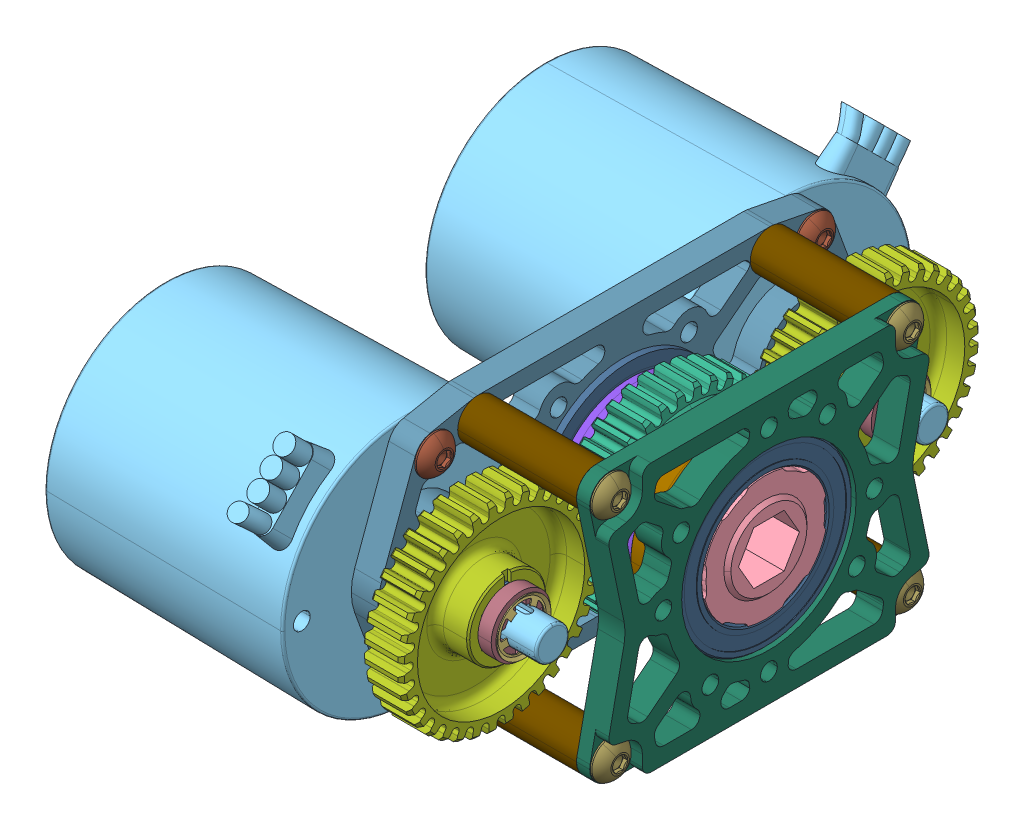
SolidWorks assembly REV Elevator Motor, configuration Default. Lengths in mm.
Overall size (99.54 69.01 161.62).
39 component instances, 18 part files, 0 mates.
Components (placement in the parent):
- REV-21-1879_For Motor Shaft, One Clip (Spaced 0.150).STEP-1: REV-21-1879_For Motor Shaft, One Clip (Spaced 0.150).STEP [Default] at (3.5 0 45.72) x (0 0 -1) z (1 0 0) size (13 13.75 24.57)
  - REV-21-1879.STEP-1: REV-21-1879.STEP [Default] at origin size (12.7 13.75 20)
  - Key_2mm_20mmLong.STEP-1: Key_2mm_20mmLong.STEP [Default] at (0.0325 4.05 10) x (0 0 -1) z (0 1 0) size (20 2 2)
  - Retaining_Ring_8mm.STEP-1: Retaining_Ring_8mm.STEP [Default] at (0 0 24.185) x (-1 0 0) z (0 0 1) size (13 13 0.76)
- REV-21-1879_For Motor Shaft, One Clip (Spaced 0.150).STEP-2: REV-21-1879_For Motor Shaft, One Clip (Spaced 0.150).STEP [Default] at (3.5 0 -45.72) x (0 -1 0) z (1 0 0) size (13 13.75 24.57)
  - REV-21-1879.STEP-1: REV-21-1879.STEP [Default] at origin size (12.7 13.75 20)
  - Key_2mm_20mmLong.STEP-1: Key_2mm_20mmLong.STEP [Default] at (0.0325 4.05 10) x (0 0 -1) z (0 1 0) size (20 2 2)
  - Retaining_Ring_8mm.STEP-1: Retaining_Ring_8mm.STEP [Default] at (0 0 24.185) x (-1 0 0) z (0 0 1) size (13 13 0.76)
- REV-21-2079.STEP-1: REV-21-2079.STEP [Default] at (20.6375 0 0) size (41.27 34.92 32.55)
- REV-21-1650.STEP-1: REV-21-1650.STEP [Default] at (0 0 -45.72) x (0 -1 0) z (1 0 0) size (65.4 64.76 93.26)
- REV-21-1650.STEP-2: REV-21-1650.STEP [Default] at (0 0 45.72) x (0 0 -1) z (1 0 0) size (65.4 64.76 93.26)
- REV-21-3012.STEP-1: REV-21-3012.STEP [Default] at (17.375 0 0) x (0 1 0) z (1 0 0) size (48.1 48.1 12.7)
- REV-21-1929.STEP-1: REV-21-1929.STEP [Default] at (17.7875 0 45.72) x (0 0 1) z (-1 0 0) size (48.2 48.2 12.7)
- REV-21-1929.STEP-2: REV-21-1929.STEP [Default] at (17.7875 0 -45.72) x (0 -0.5 0.866025) z (-1 0 0) size (48.2 48.2 12.7)
- REV-21-2541.STEP-1: REV-21-2541.STEP [Default] at (9.4375 0 0) x (0 0 -1) z (1 0 0) size (38.1 38.1 3.17)
- REV-21-2541.STEP-2: REV-21-2541.STEP [Default] at (25.4875 0 0) x (0 0 -1) z (1 0 0) size (38.1 38.1 3.17)
- REV-21-2542.STEP-1: REV-21-2542.STEP [Default] at (30.25 0 0) x (0 0 1) z (-1 0 0) size (38.1 38.1 6.35)
- F6806ZZ.STEP-1: F6806ZZ.STEP [Default] at (4.35 0 0) x (0 -0.419542 0.907736) z (-1 0 0) size (45 45 7)
- F6806ZZ.STEP-2: F6806ZZ.STEP [Default] at (36.925 0 0) x (0 -0.734429 0.678686) z (1 0 0) size (45 45 7)
- #10 Button Head Cap Screws_0.500 Long.STEP-1: #10 Button Head Cap Screws_0.500 Long.STEP [Default] at (1.2827 25.4 45.72) x (0 0.07794 -0.996958) z (1 0 0) size (9.17 9.17 15.27)
- #10 Button Head Cap Screws_0.500 Long.STEP-2: #10 Button Head Cap Screws_0.500 Long.STEP [Default] at (1.2827 -25.4 45.72) x (0 0.235024 -0.971989) z (1 0 0) size (9.17 9.17 15.27)
- #10 Button Head Cap Screws_0.500 Long.STEP-3: #10 Button Head Cap Screws_0.500 Long.STEP [Default] at (1.2827 25.4 -45.72) x (0 0.356877 -0.934151) z (1 0 0) size (9.17 9.17 15.27)
- #10 Button Head Cap Screws_0.500 Long.STEP-4: #10 Button Head Cap Screws_0.500 Long.STEP [Default] at (1.2827 -25.4 -45.72) x (0 0.442397 -0.896819) z (1 0 0) size (9.17 9.17 15.27)
- #10 Button Head Cap Screws_1.500 Long.STEP-1: #10 Button Head Cap Screws_1.500 Long.STEP [Default] at (20.3327 27.454 35.2002) x (0 -0.07794 0.996958) z (1 0 0) size (9.17 9.17 40.67)
- #10 Button Head Cap Screws_1.500 Long.STEP-2: #10 Button Head Cap Screws_1.500 Long.STEP [Default] at (20.3327 27.454 -35.2002) x (0 -0.235024 0.971989) z (1 0 0) size (9.17 9.17 40.67)
- #10 Button Head Cap Screws_1.500 Long.STEP-3: #10 Button Head Cap Screws_1.500 Long.STEP [Default] at (20.3327 -27.454 -35.2002) x (0 -0.356877 0.934151) z (1 0 0) size (9.17 9.17 40.67)
- #10 Button Head Cap Screws_1.500 Long.STEP-4: #10 Button Head Cap Screws_1.500 Long.STEP [Default] at (20.3327 -27.454 35.2002) x (0 -0.442397 0.896819) z (1 0 0) size (9.17 9.17 40.67)
- REV-21-2078.STEP-1: REV-21-2078.STEP [Default] at (25.725 0 45.72) x (0 0 1) z (-1 0 0) size (14.29 14.29 3.17)
- REV-21-2078.STEP-2: REV-21-2078.STEP [Default] at (25.725 0 -45.72) x (0 1 0) z (-1 0 0) size (14.29 14.29 3.17)
- REV-21-2099-P01.STEP-1: REV-21-2099-P01.STEP [Default] at origin size (6.35 64.43 118.43)
- REV-21-2099-P02.STEP-1: REV-21-2099-P02.STEP [Default] at (34.925 0 0) size (6.35 64.43 79.93)
- REV-21-2005.STEP-1: REV-21-2005.STEP [Default] at (6.675 0 45.72) x (0 0 -1) z (1 0 0) size (18.29 18.29 6.35)
- REV-21-2003.STEP-1: REV-21-2003.STEP [Default] at (10.6438 0 45.72) x (0 0 -1) z (1 0 0) size (18.29 18.29 1.59)
- REV-21-2003.STEP-2: REV-21-2003.STEP [Default] at (10.6438 0 -45.72) x (0 0 -1) z (1 0 0) size (18.29 18.29 1.59)
- REV-21-2005.STEP-2: REV-21-2005.STEP [Default] at (6.675 0 -45.72) x (0 0 -1) z (1 0 0) size (18.29 18.29 6.35)
- #10 Unthreaded Spacers_1.125in Long.STEP-1: #10 Unthreaded Spacers_1.125in Long.STEP [Default] at (20.6375 27.454 35.2002) size (28.57 9.53 9.53)
- #10 Unthreaded Spacers_1.125in Long.STEP-2: #10 Unthreaded Spacers_1.125in Long.STEP [Default] at (20.6375 -27.454 35.2002) size (28.57 9.53 9.53)
- #10 Unthreaded Spacers_1.125in Long.STEP-3: #10 Unthreaded Spacers_1.125in Long.STEP [Default] at (20.6375 27.454 -35.2002) size (28.57 9.53 9.53)
- #10 Unthreaded Spacers_1.125in Long.STEP-4: #10 Unthreaded Spacers_1.125in Long.STEP [Default] at (20.6375 -27.454 -35.2002) size (28.57 9.53 9.53)
